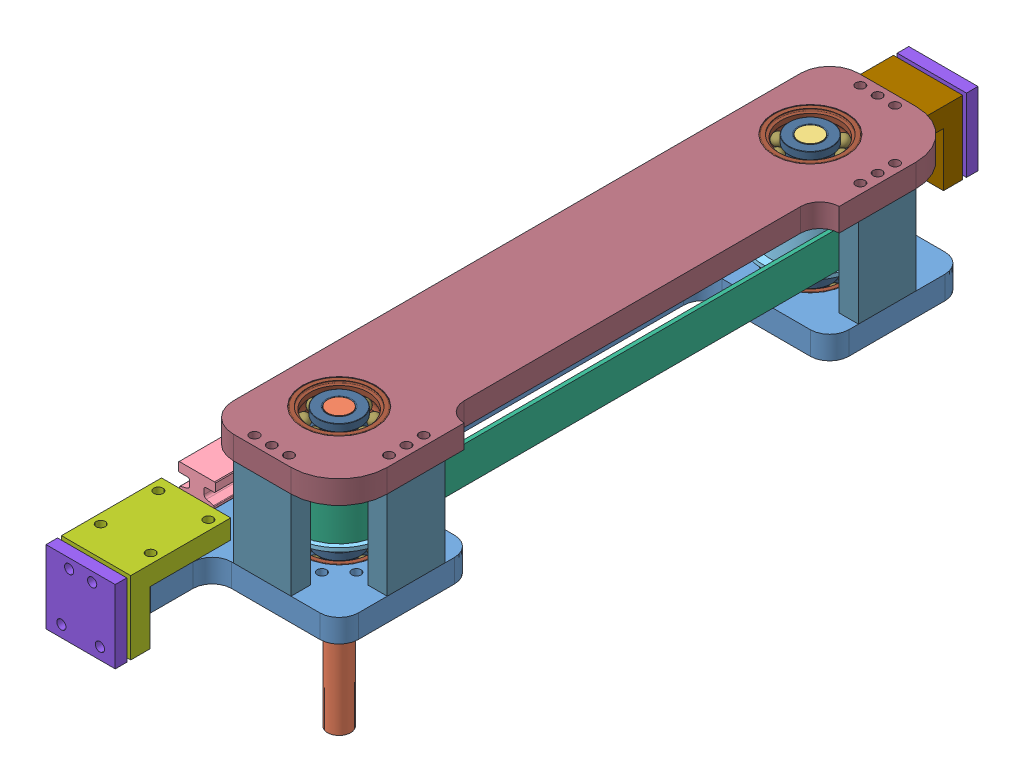
SolidWorks assembly eixo_y_assemb, configuration Default. Lengths in mm.
Overall size (51.28 72 224.28).
64 component instances, 15 part files, 30 mates.
Components (placement in the parent):
- suporte_guia-1: suporte_guia [Default] at (-18.1275 1.9524 77.3828) size (50.98 6 178.5)
- veio_motor_polia-1: veio_motor_polia [Default] at (12.8525 -35.0476 41.3828) x (0.944162 0 0.329483) z (-0.329483 0 0.944162) size (6 72 6)
- veio_polia2-1: veio_polia2 [Default] at (12.8525 1.9524 -81.1172) size (6 35 6)
- guia_T_120mm-1: guia_T_120mm [Default] at (-13.6275 7.9524 -8.1172) x (1 0 0) z (0 1 0) size (9.6 120 6.3)
- polia-1: polia [Default] at (12.8525 32.9524 41.3828) x (-0.837169 0 -0.546944) z (-0.546944 0 0.837169) size (25 20 25)
- polia-2: polia [Default] at (12.8525 32.9524 -81.1172) x (-0.837169 0 -0.546944) z (-0.546944 0 0.837169) size (25 20 25)
- correia_y-1: correia_y [Default] at (12.8525 13.9524 41.3828) x (0 0 -1) z (1 0 0) size (145.07 9.53 22.57)
- aperto_total-2: aperto_total [Default] at (-11.034 -0.6605 73.5433) size (18 19 30.02)
  - aperto-1: aperto [Default] at (-7.0935 8.6129 9.0395) size (18 19 26)
  - aperto_chapa-1: aperto_chapa [Default] at (-7.0935 -5.3871 10.0595) size (18 19 3)
- aperto_total_comp-1: aperto_total_comp [Default] at (-14.1313 -0.7616 -121.0899) x (-1 0 0) z (0 0 -1) size (18 19 64.56)
  - aperto_comp-1: aperto_comp [Default] at (-14.0038 8.7139 12.6173) size (18 19 60.59)
  - aperto_chapa-1: aperto_chapa [Default] at (-14.0038 -5.2861 13.5873) size (18 19 3)
- 626-1: 626 [Default] at (12.8525 1.9524 41.3828) x (0 1 0) z (0 0 1) size (6 19 19)
  - 626_PART1-1: 626_PART1 [Default] at origin size (6 11.1 11.1)
  - 626_PART2-1: 626_PART2 [Default] at origin size (6 19 19)
  - 626_PART3-1: 626_PART3 [Default] at origin size (3 3 3)
  - 626_PART3-2: 626_PART3 [Default] x (1 0 0) z (0 0.707107 0.707107) size (3 3 3)
  - 626_PART3-3: 626_PART3 [Default] x (1 0 0) z (0 1 0) size (3 3 3)
  - 626_PART3-4: 626_PART3 [Default] x (1 0 0) z (0 0.707107 -0.707107) size (3 3 3)
  - 626_PART3-5: 626_PART3 [Default] x (1 0 0) z (0 0 -1) size (3 3 3)
  - 626_PART3-6: 626_PART3 [Default] x (1 0 0) z (0 -0.707107 -0.707107) size (3 3 3)
  - 626_PART3-7: 626_PART3 [Default] x (1 0 0) z (0 -1 0) size (3 3 3)
  - 626_PART3-8: 626_PART3 [Default] x (1 0 0) z (0 -0.707107 0.707107) size (3 3 3)
- 626-2: 626 [Default] at (12.8525 1.9524 -81.1172) x (0 1 0) z (0 0 1) size (6 19 19)
  - 626_PART1-1: 626_PART1 [Default] at origin size (6 11.1 11.1)
  - 626_PART2-1: 626_PART2 [Default] at origin size (6 19 19)
  - 626_PART3-1: 626_PART3 [Default] at origin size (3 3 3)
  - 626_PART3-2: 626_PART3 [Default] x (1 0 0) z (0 0.707107 0.707107) size (3 3 3)
  - 626_PART3-3: 626_PART3 [Default] x (1 0 0) z (0 1 0) size (3 3 3)
  - 626_PART3-4: 626_PART3 [Default] x (1 0 0) z (0 0.707107 -0.707107) size (3 3 3)
  - 626_PART3-5: 626_PART3 [Default] x (1 0 0) z (0 0 -1) size (3 3 3)
  - 626_PART3-6: 626_PART3 [Default] x (1 0 0) z (0 -0.707107 -0.707107) size (3 3 3)
  - 626_PART3-7: 626_PART3 [Default] x (1 0 0) z (0 -1 0) size (3 3 3)
  - 626_PART3-8: 626_PART3 [Default] x (1 0 0) z (0 -0.707107 0.707107) size (3 3 3)
- sup_motor_veio_polia-1: sup_motor_veio_polia [Default] at (15.9961 37.1054 46.7047) size (35 29 162.5)
  - sup_veio_eixo_y-1: sup_veio_eixo_y [Default] at (-18.1436 -0.153 9.6781) size (35 6 162.5)
  - sup__alt_motor_veio_polia-1: sup__alt_motor_veio_polia [Default] at (-3.1436 -6.153 12.1781) size (15 23 5)
  - sup__alt_motor_veio_polia-3: sup__alt_motor_veio_polia [Default] at (14.3564 -6.153 -5.3219) x (0 0 1) z (-1 0 0) size (15 23 5)
  - 626-1: 626 [Default] at (-3.1436 -0.153 -127.8219) x (0 -1 0) z (-0.350967 0 -0.936388) size (6 19 19)
    - 626_PART1-1: 626_PART1 [Default] at origin size (6 11.1 11.1)
    - 626_PART2-1: 626_PART2 [Default] at origin size (6 19 19)
    - 626_PART3-1: 626_PART3 [Default] at origin size (3 3 3)
    - 626_PART3-2: 626_PART3 [Default] x (1 0 0) z (0 0.707107 0.707107) size (3 3 3)
    - 626_PART3-3: 626_PART3 [Default] x (1 0 0) z (0 1 0) size (3 3 3)
    - 626_PART3-4: 626_PART3 [Default] x (1 0 0) z (0 0.707107 -0.707107) size (3 3 3)
    - 626_PART3-5: 626_PART3 [Default] x (1 0 0) z (0 0 -1) size (3 3 3)
    - 626_PART3-6: 626_PART3 [Default] x (1 0 0) z (0 -0.707107 -0.707107) size (3 3 3)
    - 626_PART3-7: 626_PART3 [Default] x (1 0 0) z (0 -1 0) size (3 3 3)
    - 626_PART3-8: 626_PART3 [Default] x (1 0 0) z (0 -0.707107 0.707107) size (3 3 3)
  - 626-2: 626 [Default] at (-3.1436 -0.153 -5.3219) x (0 -1 0) z (0 0 1) size (6 19 19)
    - 626_PART1-1: 626_PART1 [Default] at origin size (6 11.1 11.1)
    - 626_PART2-1: 626_PART2 [Default] at origin size (6 19 19)
    - 626_PART3-1: 626_PART3 [Default] at origin size (3 3 3)
    - 626_PART3-2: 626_PART3 [Default] x (1 0 0) z (0 0.707107 0.707107) size (3 3 3)
    - 626_PART3-3: 626_PART3 [Default] x (1 0 0) z (0 1 0) size (3 3 3)
    - 626_PART3-4: 626_PART3 [Default] x (1 0 0) z (0 0.707107 -0.707107) size (3 3 3)
    - 626_PART3-5: 626_PART3 [Default] x (1 0 0) z (0 0 -1) size (3 3 3)
    - 626_PART3-6: 626_PART3 [Default] x (1 0 0) z (0 -0.707107 -0.707107) size (3 3 3)
    - 626_PART3-7: 626_PART3 [Default] x (1 0 0) z (0 -1 0) size (3 3 3)
    - 626_PART3-8: 626_PART3 [Default] x (1 0 0) z (0 -0.707107 0.707107) size (3 3 3)
  - sup__alt_motor_veio_polia-5: sup__alt_motor_veio_polia [Default] at (14.3564 -6.153 -127.8219) x (0 0 1) z (-1 0 0) size (15 23 5)
  - sup__alt_motor_veio_polia-6: sup__alt_motor_veio_polia [Default] at (-3.1436 -6.153 -145.3219) size (15 23 5)
- batente-1: batente [Default] at (-18.1275 7.9524 -68.1172) size (9.6 9.81 5)
Mates (geometry in assembly coordinates):
- Concentric1: concentric anti-aligned: cylinder of suporte_guia-1 through (12.8525 1.9523 41.3828) axis (0 1 0) radius 9.5; cylinder of veio_motor_polia-1 through (12.8525 36.9524 41.3828) axis (0 -1 0) radius 3
- Distance1: distance = 29 mm aligned: plane of veio_motor_polia-1 through (12.8525 36.9524 41.3828) normal (0 1 0); plane of suporte_guia-1 through (-18.1275 7.9524 -94.6172) normal (0 1 0)
- Concentric2: concentric anti-aligned: cylinder of suporte_guia-1 through (12.8525 1.9523 -81.1172) axis (0 1 0) radius 9.5; cylinder of veio_polia2-1 through (12.8525 36.9524 -81.1172) axis (0 -1 0) radius 3
- Coincident2: coincident anti-aligned: plane of suporte_guia-1 through (-18.1275 1.9524 -94.6172) normal (0 -1 0); circle of veio_polia2-1
- Coincident5: coincident anti-aligned: plane of suporte_guia-1 through (-18.1275 7.9524 -94.6172) normal (0 1 0); plane of guia_T_120mm-1 through (-9.1275 7.9524 -68.1172) normal (0 -1 0)
- Concentric5: concentric aligned: cylinder of guia_T_120mm-1 through (-13.6275 14.2524 -58.1172) axis (0 1 0) radius 1.2; cylinder of suporte_guia-1 through (-13.6275 7.9524 -58.1172) axis (0 1 0) radius 0.8
- Concentric6: concentric aligned: cylinder of suporte_guia-1 through (-13.6275 7.9524 1.8828) axis (0 1 0) radius 0.8; cylinder of guia_T_120mm-1 through (-13.6275 14.2524 1.8828) axis (0 1 0) radius 1.2
- Distance2: distance = 5 mm anti-aligned: plane of polia-1 through (2.3879 12.9524 34.546) normal (0 -1 0); plane of suporte_guia-1 through (-18.1275 7.9524 -94.6172) normal (0 1 0)
- Concentric7: concentric anti-aligned: cylinder of veio_motor_polia-1 through (12.8525 36.9524 41.3828) axis (0 -1 0) radius 3; cylinder of polia-1 through (12.8525 12.9524 41.3828) axis (0 1 0) radius 3
- Coincident9: coincident aligned: plane of polia-1 through (2.3879 12.9524 34.546) normal (0 -1 0); plane of polia-2 through (2.3879 12.9524 -87.954) normal (0 -1 0)
- Concentric8: concentric anti-aligned: cylinder of veio_polia2-1 through (12.8525 36.9524 -81.1172) axis (0 -1 0) radius 3; cylinder of polia-2 through (12.8525 12.9524 -81.1172) axis (0 1 0) radius 3
- Concentric9: concentric aligned: cylinder of polia-1 through (12.8525 32.9524 41.3828) axis (0 1 0) radius 10.255; cylinder of correia_y-1 through (12.8525 13.9524 41.3828) axis (0 1 0) radius 10.255
- Concentric10: concentric aligned: cylinder of polia-2 through (12.8525 32.9524 -81.1172) axis (0 1 0) radius 10.255; cylinder of correia_y-1 through (12.8525 13.9524 -81.1172) axis (0 1 0) radius 10.255
- Coincident10: coincident anti-aligned: plane of polia-1 through (4.2674 13.9524 35.7739) normal (0 1 0); plane of correia_y-1 through (12.8525 13.9524 41.3828) normal (0 -1 0)
- Coincident13: coincident anti-aligned: plane of suporte_guia-1 through (-18.1275 7.9524 -94.6172) normal (0 1 0); plane of aperto_total-2/aperto-1 through (-18.1275 7.9524 56.5828) normal (0 -1 0)
- Concentric15: concentric aligned: cylinder of aperto_total-2/aperto-1 through (-2.6275 12.9524 74.8828) axis (0 1 0) radius 1.2; cylinder of suporte_guia-1 through (-2.6275 7.9524 74.8828) axis (0 1 0) radius 1.2
- Concentric16: concentric aligned: cylinder of aperto_total-2/aperto-1 through (-15.6275 12.9524 74.8828) axis (0 1 0) radius 1.2; cylinder of suporte_guia-1 through (-15.6275 7.9524 74.8828) axis (0 1 0) radius 1.2
- Coincident14: coincident anti-aligned: plane of suporte_guia-1 through (-18.1275 7.9524 -94.6172) normal (0 1 0); plane of aperto_total_comp-1/aperto_comp-1 through (-0.1275 7.9524 -73.1172) normal (0 -1 0)
- Concentric18: concentric aligned: cylinder of aperto_total_comp-1/aperto_comp-1 through (-2.6275 12.9524 -92.1172) axis (0 1 0) radius 1.2; cylinder of suporte_guia-1 through (-2.6275 7.9524 -92.1172) axis (0 1 0) radius 1.2
- Concentric19: concentric aligned: cylinder of aperto_total_comp-1/aperto_comp-1 through (-15.6275 12.9524 -92.1172) axis (0 1 0) radius 1.2; cylinder of suporte_guia-1 through (-15.6275 7.9524 -92.1172) axis (0 1 0) radius 1.2
- Concentric20: concentric anti-aligned: cylinder of veio_motor_polia-1 through (12.8525 36.9524 41.3828) axis (0 -1 0) radius 3; cylinder of 626-1/626_PART1-1 through (12.8525 7.6524 41.3828) axis (0 1 0) radius 3
- Coincident15: coincident aligned: plane of suporte_guia-1 through (-18.1275 7.9524 -94.6172) normal (0 1 0); plane of 626-1/626_PART1-1 through (9.5525 7.9524 41.3828) normal (0 1 0)
- Concentric21: concentric anti-aligned: cylinder of veio_polia2-1 through (12.8525 36.9524 -81.1172) axis (0 -1 0) radius 3; cylinder of 626-2/626_PART1-1 through (12.8525 7.6524 -81.1172) axis (0 1 0) radius 3
- Coincident16: coincident aligned: plane of suporte_guia-1 through (-18.1275 7.9524 -94.6172) normal (0 1 0); plane of 626-2/626_PART1-1 through (9.5525 7.9524 -81.1172) normal (0 1 0)
- Coincident17: coincident aligned: plane of veio_motor_polia-1 through (12.8525 36.9524 41.3828) normal (0 1 0); plane of sup_motor_veio_polia-1/sup_veio_eixo_y-1 through (-2.1475 36.9524 -96.1172) normal (0 1 0)
- Concentric22: concentric anti-aligned: cylinder of veio_motor_polia-1 through (12.8525 36.9524 41.3828) axis (0 -1 0) radius 3; cylinder of sup_motor_veio_polia-1/sup_veio_eixo_y-1 through (12.8525 30.9524 41.3828) axis (0 1 0) radius 9.5
- Concentric23: concentric aligned: cylinder of veio_polia2-1 through (12.8525 36.9524 -81.1172) axis (0 -1 0) radius 3; cylinder of ? through (12.8525 31.2524 -81.1172) axis (0 -1 0) radius 3
- Coincident18: coincident anti-aligned: plane of suporte_guia-1 through (-18.1275 7.9524 -94.6172) normal (0 1 0); plane of batente-1 through (-18.1275 7.9524 -73.1172) normal (0 -1 0)
- Coincident19: coincident anti-aligned: plane of guia_T_120mm-1 through (-9.1275 7.9524 -68.1172) normal (0 0 -1); plane of batente-1 through (-18.1275 17.767 -68.1172) normal (0 0 1)
- Coincident21: coincident aligned: plane of suporte_guia-1 through (-18.1275 7.9524 77.3828) normal (-1 0 0); plane of batente-1 through (-18.1275 7.9524 -73.1172) normal (-1 0 0)
